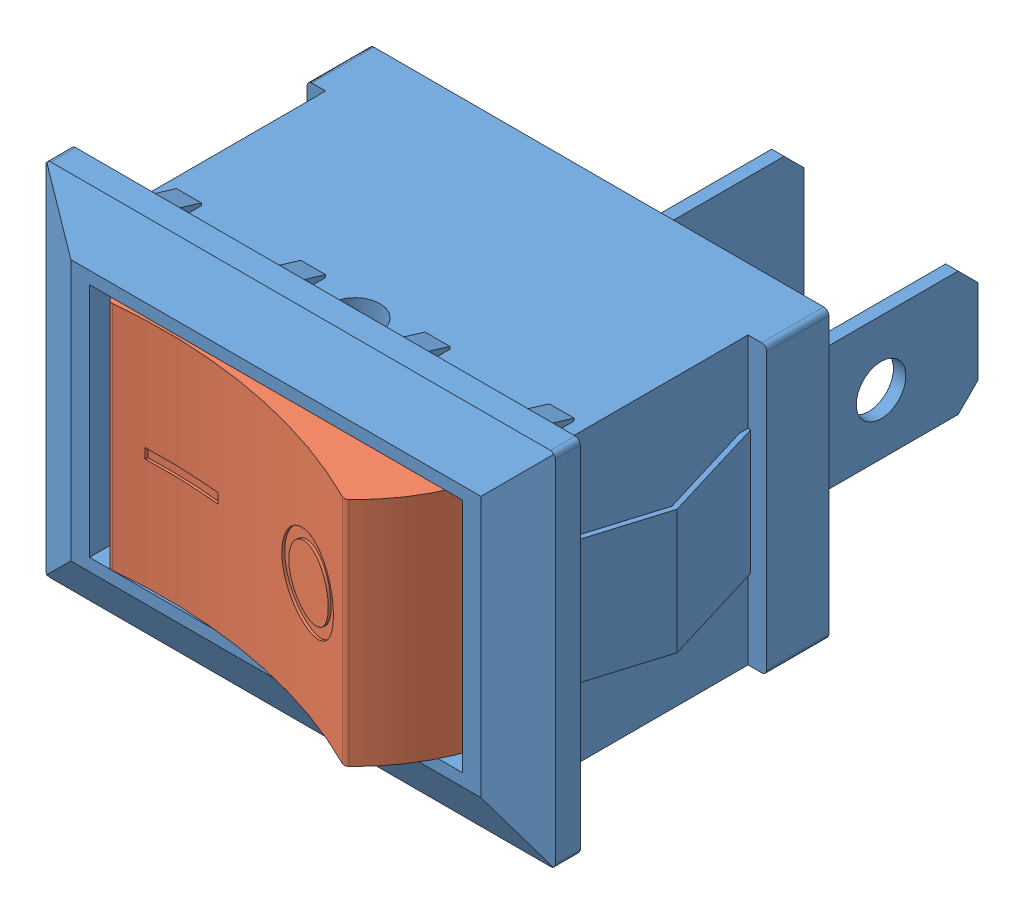
SolidWorks assembly kcd1.stp, configuration Default. Lengths in mm.
Overall size (20.5 14.5 23.5).
2 component instances, 2 part files, 0 mates.
Components (placement in the parent):
- kcd1-prt0.stp-1: kcd1-prt0.stp [Default] at origin size (20.5 14.5 21)
- kcd1-prt1.stp-1: kcd1-prt1.stp [Default] at (1.7891 0 0.1645) x (0.983241 0 0.182313) z (-0.182313 0 0.983241) size (14.8 11.5 6.42)
